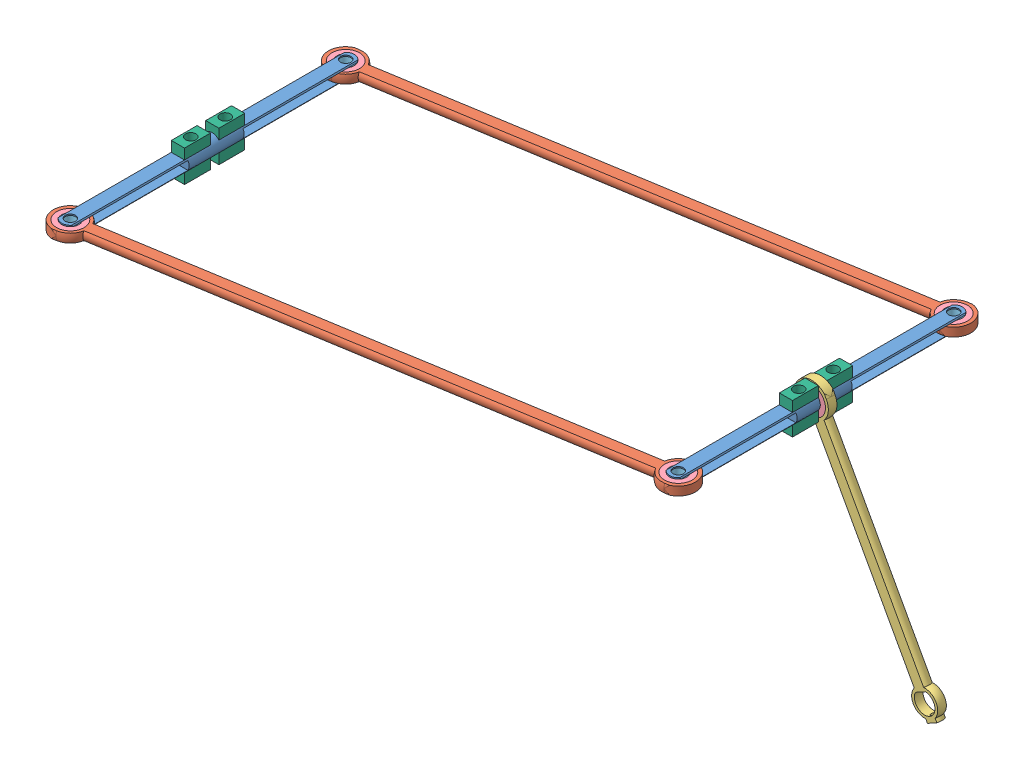
SolidWorks assembly 单臂, configuration 默认. Lengths in mm.
Overall size (196.95 72.97 116.28).
22 component instances, 6 part files, 52 mates.
Components (placement in the parent):
- 关节-1: 关节 [默认] at (38.3387 -1.1505 -161.6361) size (5 5 85)
- 关节-2: 关节 [默认] at (-113.5016 -1.1505 -136.8395) size (5 5 85)
- 长臂-1: 长臂 [默认] at (-126.4048 -1.1505 -124.7323) x (0.986926 0 -0.161172) z (0.161172 0 0.986926) size (163.85 2.5 10)
- 长臂-2: 长臂 [默认] at (-126.4048 -1.1505 -44.7323) x (0.986926 0 -0.161172) z (0.161172 0 0.986926) size (163.85 2.5 10)
- 短臂-1: 短臂 [默认] at (78.8008 -74.9015 -111.6361) x (-0.480997 0.876722 0) z (0.876722 0.480997 0) size (77.74 2.5 10)
- 轴承_MR85ZZ-1: 轴承_MR85ZZ [默认] at (38.3387 -1.1505 -112.8861) size (8 8 2.5)
- 轴承_MR85ZZ-2: 轴承_MR85ZZ [默认] at (38.3387 0.0995 -71.6361) x (1 0 0) z (0 -1 0) size (8 8 2.5)
- 轴承_MR85ZZ-3: 轴承_MR85ZZ [默认] at (-113.5016 0.0995 -46.8395) x (1 0 0) z (0 -1 0) size (8 8 2.5)
- 轴承_MR85ZZ-4: 轴承_MR85ZZ [默认] at (-113.5016 0.0995 -126.8395) x (1 0 0) z (0 -1 0) size (8 8 2.5)
- 轴承_MR85ZZ-5: 轴承_MR85ZZ [默认] at (38.3387 0.0995 -151.6361) x (1 0 0) z (0 -1 0) size (8 8 2.5)
- 长臂_关节连接件-1: 长臂_关节连接件 [默认] at (-113.5016 -2.4005 -126.8395) x (1 0 0) z (0 1 0) size (5 5 2.5)
- 长臂_关节连接件-2: 长臂_关节连接件 [默认] at (38.3387 0.0995 -151.6361) x (1 0 0) z (0 -1 0) size (5 5 2.5)
- 长臂_关节连接件-3: 长臂_关节连接件 [默认] at (38.3387 0.0995 -71.6361) x (1 0 0) z (0 -1 0) size (5 5 2.5)
- 长臂_关节连接件-4: 长臂_关节连接件 [默认] at (-113.5016 0.0995 -46.8395) x (1 0 0) z (0 -1 0) size (5 5 2.5)
- 短臂-关节轴承限位件-1: 短臂-关节轴承限位件 [默认] at (-115.3656 3.4495 -82.9304) x (0 0 1) z (0 -1 0) size (7.5 3.84 3)
- 短臂-关节轴承限位件-2: 短臂-关节轴承限位件 [默认] at (-115.3656 -2.7505 -92.9304) x (0 0 1) z (0 -1 0) size (7.5 3.84 3)
- 短臂-关节轴承限位件-3: 短臂-关节轴承限位件 [默认] at (-115.3656 3.4495 -92.9304) x (0 0 1) z (0 -1 0) size (7.5 3.84 3)
- 短臂-关节轴承限位件-4: 短臂-关节轴承限位件 [默认] at (-115.3656 -2.7505 -82.9304) x (0 0 1) z (0 -1 0) size (7.5 3.84 3)
- 短臂-关节轴承限位件-5: 短臂-关节轴承限位件 [默认] at (36.4746 -2.7505 -117.727) x (0 0 1) z (0 -1 0) size (7.5 3.84 3)
- 短臂-关节轴承限位件-6: 短臂-关节轴承限位件 [默认] at (36.4746 3.4495 -107.727) x (0 0 1) z (0 -1 0) size (7.5 3.84 3)
- 短臂-关节轴承限位件-7: 短臂-关节轴承限位件 [默认] at (36.4746 3.4495 -117.727) x (0 0 1) z (0 -1 0) size (7.5 3.84 3)
- 短臂-关节轴承限位件-8: 短臂-关节轴承限位件 [默认] at (36.4746 -2.7505 -107.727) x (0 0 1) z (0 -1 0) size (7.5 3.84 3)
Mates (geometry in assembly coordinates):
- 同心3: concentric aligned: cylinder of 关节-1 through (38.3387 -1.1505 -61.6361) axis (0 0 -1) radius 2.5; cylinder of 轴承_MR85ZZ-1 through (38.3387 -1.1505 -110.3861) axis (0 0 -1) radius 2.5
- 重合2: coincident aligned: plane of 关节-1 through (38.3387 -1.1505 -110.3861) normal (0 0 1); plane of 轴承_MR85ZZ-1 through (38.3387 -1.1505 -110.3861) normal (0 0 1)
- 同心4: concentric anti-aligned: cylinder of 关节-1 through (38.3387 20.8495 -71.6361) axis (0 -1 0) radius 1.5; cylinder of 轴承_MR85ZZ-2 through (38.3387 -2.4005 -71.6361) axis (0 1 0) radius 2.5
- 重合4: coincident anti-aligned: plane of 关节-1 through (60.3387 0.0995 -39.6361) normal (0 -1 0); plane of 轴承_MR85ZZ-2 through (38.3387 0.0995 -71.6361) normal (0 1 0)
- 重合7: coincident anti-aligned: plane of 关节-1 through (60.3387 0.0995 -183.6361) normal (0 -1 0); plane of 轴承_MR85ZZ-5 through (38.3387 0.0995 -151.6361) normal (0 1 0)
- 同心7: concentric anti-aligned: cylinder of 关节-1 through (38.3387 20.8495 -151.6361) axis (0 -1 0) radius 1.5; cylinder of 轴承_MR85ZZ-5 through (38.3387 -2.4005 -151.6361) axis (0 1 0) radius 2.5
- 同心10: concentric aligned: cylinder of 轴承_MR85ZZ-3 through (-113.5016 -2.4005 -46.8395) axis (0 1 0) radius 2.5; circle of 关节-2
- 重合10: coincident anti-aligned: plane of 轴承_MR85ZZ-3 through (-113.5016 0.0995 -46.8395) normal (0 1 0); plane of 关节-2 through (-91.5016 0.0995 -14.8395) normal (0 -1 0)
- 重合11: coincident anti-aligned: plane of 轴承_MR85ZZ-4 through (-113.5016 0.0995 -126.8395) normal (0 1 0); plane of 关节-2 through (-91.5016 0.0995 -158.8395) normal (0 -1 0)
- 同心11: concentric anti-aligned: cylinder of 关节-2 through (-113.5016 20.8495 -126.8395) axis (0 -1 0) radius 1.5; cylinder of 轴承_MR85ZZ-4 through (-113.5016 -2.4005 -126.8395) axis (0 1 0) radius 2.5
- 同心6: concentric anti-aligned: cylinder of 长臂-1 through (38.3387 168.8495 -151.6361) axis (0 -1 0) radius 4; cylinder of 轴承_MR85ZZ-5 through (38.3387 -2.4005 -151.6361) axis (0 1 0) radius 4
- 重合6: coincident aligned: plane of 长臂-1 through (51.2419 0.0995 -153.7433) normal (0 1 0); plane of 轴承_MR85ZZ-5 through (38.3387 0.0995 -151.6361) normal (0 1 0)
- 同心9: concentric anti-aligned: cylinder of 长臂-1 through (-113.5016 168.8495 -126.8395) axis (0 -1 0) radius 4; cylinder of 轴承_MR85ZZ-4 through (-113.5016 -2.4005 -126.8395) axis (0 1 0) radius 4
- 重合9: coincident aligned: plane of 长臂-1 through (51.2419 0.0995 -153.7433) normal (0 1 0); plane of 轴承_MR85ZZ-4 through (-113.5016 0.0995 -126.8395) normal (0 1 0)
- 重合5: coincident aligned: plane of 长臂-2 through (51.2419 0.0995 -73.7433) normal (0 1 0); plane of 轴承_MR85ZZ-2 through (38.3387 0.0995 -71.6361) normal (0 1 0)
- 同心5: concentric anti-aligned: cylinder of 长臂-2 through (38.3387 168.8495 -71.6361) axis (0 -1 0) radius 4; cylinder of 轴承_MR85ZZ-2 through (38.3387 -2.4005 -71.6361) axis (0 1 0) radius 4
- 同心8: concentric anti-aligned: cylinder of 长臂-2 through (-113.5016 168.8495 -46.8395) axis (0 -1 0) radius 4; cylinder of 轴承_MR85ZZ-3 through (-113.5016 -2.4005 -46.8395) axis (0 1 0) radius 4
- 重合8: coincident aligned: plane of 长臂-2 through (51.2419 0.0995 -73.7433) normal (0 1 0); plane of 轴承_MR85ZZ-3 through (-113.5016 0.0995 -46.8395) normal (0 1 0)
- 同心2: concentric anti-aligned: cylinder of 轴承_MR85ZZ-1 through (38.3387 -1.1505 -110.3861) axis (0 0 -1) radius 4; cylinder of 短臂-1 through (38.3387 -1.1505 -210.3861) axis (0 0 1) radius 4
- 重合1: coincident aligned: plane of 轴承_MR85ZZ-1 through (38.3387 -1.1505 -110.3861) normal (0 0 1); plane of 短臂-1 through (30.7011 12.7707 -110.3861) normal (0 0 1)
- 同心12: concentric anti-aligned: cylinder of 轴承_MR85ZZ-4 through (-113.5016 -2.4005 -126.8395) axis (0 1 0) radius 2.5; cylinder of 长臂_关节连接件-1 through (-113.5016 0.0995 -126.8395) axis (0 -1 0) radius 2.5
- 重合12: coincident aligned: plane of 轴承_MR85ZZ-4 through (-113.5016 0.0995 -126.8395) normal (0 1 0); plane of 长臂_关节连接件-1 through (-113.5016 0.0995 -126.8395) normal (0 1 0)
- 同心13: concentric anti-aligned: cylinder of 关节-2 through (-113.5016 20.8495 -46.8395) axis (0 -1 0) radius 1.5; cylinder of 长臂_关节连接件-4 through (-113.5016 -2.4005 -46.8395) axis (0 1 0) radius 1.5
- 重合13: coincident aligned: plane of 轴承_MR85ZZ-3 through (-113.5016 0.0995 -46.8395) normal (0 1 0); plane of 长臂_关节连接件-4 through (-113.5016 0.0995 -46.8395) normal (0 1 0)
- 同心14: concentric anti-aligned: cylinder of 关节-1 through (38.3387 20.8495 -151.6361) axis (0 -1 0) radius 1.5; cylinder of 长臂_关节连接件-2 through (38.3387 -2.4005 -151.6361) axis (0 1 0) radius 1.5
- 重合14: coincident aligned: plane of 轴承_MR85ZZ-5 through (38.3387 0.0995 -151.6361) normal (0 1 0); plane of 长臂_关节连接件-2 through (38.3387 0.0995 -151.6361) normal (0 1 0)
- 同心15: concentric anti-aligned: cylinder of 关节-1 through (38.3387 20.8495 -71.6361) axis (0 -1 0) radius 1.5; cylinder of 长臂_关节连接件-3 through (38.3387 -2.4005 -71.6361) axis (0 1 0) radius 1.5
- 重合15: coincident aligned: plane of 轴承_MR85ZZ-2 through (38.3387 0.0995 -71.6361) normal (0 1 0); plane of 长臂_关节连接件-3 through (38.3387 0.0995 -71.6361) normal (0 1 0)
- 同心16: concentric anti-aligned: cylinder of 关节-2 through (-113.5016 20.8495 -81.8395) axis (0 -1 0) radius 1.5; cylinder of 短臂-关节轴承限位件-1 through (-113.5016 0.4495 -81.8395) axis (0 1 0) radius 1.5
- 重合16: coincident anti-aligned: plane of 关节-2 through (-113.5016 -1.1505 -85.5895) normal (0 0 1); plane of 短臂-关节轴承限位件-1 through (-115.4216 0.4495 -85.5895) normal (0 0 -1)
- 重合19: coincident anti-aligned: plane of 关节-2 through (-113.5016 -1.1505 -88.0895) normal (0 0 -1); plane of 短臂-关节轴承限位件-3 through (-115.4216 0.4495 -88.0895) normal (0 0 1)
- 同心19: concentric anti-aligned: cylinder of 关节-2 through (-113.5016 20.8495 -91.8395) axis (0 -1 0) radius 1.5; cylinder of 短臂-关节轴承限位件-3 through (-113.5016 0.4495 -91.8395) axis (0 1 0) radius 1.5
- 重合20: coincident anti-aligned: plane of 关节-2 through (-113.5016 -1.1505 -88.0895) normal (0 0 -1); plane of 短臂-关节轴承限位件-2 through (-115.4216 -5.7505 -88.0895) normal (0 0 1)
- 同心21: concentric anti-aligned: cylinder of 关节-2 through (-113.5016 20.8495 -91.8395) axis (0 -1 0) radius 1.5; cylinder of 短臂-关节轴承限位件-2 through (-113.5016 -5.7505 -91.8395) axis (0 1 0) radius 1.5
- 重合21: coincident anti-aligned: plane of 关节-2 through (-113.5016 -2.7505 -36.8395) normal (0 -1 0); plane of 短臂-关节轴承限位件-2 through (-115.3656 -2.7505 -92.9304) normal (0 1 0)
- 重合22: coincident: plane of 关节-2 through (-113.5016 0.4495 -36.8395) normal (0 1 0); line of 短臂-关节轴承限位件-3 through (-115.4216 0.4495 -88.0895) axis (0 0 -1)
- 重合23: coincident anti-aligned: plane of 关节-2 through (-113.5016 0.4495 -136.8395) normal (0 1 0); plane of 短臂-关节轴承限位件-1 through (-115.3656 0.4495 -82.9304) normal (0 -1 0)
- 重合24: coincident anti-aligned: plane of 关节-2 through (-113.5016 -2.7505 -136.8395) normal (0 -1 0); plane of 短臂-关节轴承限位件-4 through (-115.3656 -2.7505 -82.9304) normal (0 1 0)
- 同心22: concentric anti-aligned: cylinder of 关节-2 through (-113.5016 20.8495 -81.8395) axis (0 -1 0) radius 1.5; cylinder of 短臂-关节轴承限位件-4 through (-113.5016 -5.7505 -81.8395) axis (0 1 0) radius 1.5
- 重合25: coincident anti-aligned: plane of 关节-2 through (-113.5016 -1.1505 -85.5895) normal (0 0 1); plane of 短臂-关节轴承限位件-4 through (-115.4216 -5.7505 -85.5895) normal (0 0 -1)
- 同心23: concentric anti-aligned: cylinder of 关节-1 through (38.3387 20.8495 -106.6361) axis (0 -1 0) radius 1.5; cylinder of 短臂-关节轴承限位件-6 through (38.3387 0.4495 -106.6361) axis (0 1 0) radius 1.5
- 重合26: coincident anti-aligned: plane of 关节-1 through (38.3387 0.4495 -161.6361) normal (0 1 0); plane of 短臂-关节轴承限位件-6 through (36.4746 0.4495 -107.727) normal (0 -1 0)
- 重合27: coincident anti-aligned: plane of 关节-1 through (38.3387 -2.7505 -161.6361) normal (0 -1 0); plane of 短臂-关节轴承限位件-8 through (36.4746 -2.7505 -107.727) normal (0 1 0)
- 同心24: concentric anti-aligned: cylinder of 关节-1 through (38.3387 20.8495 -106.6361) axis (0 -1 0) radius 1.5; cylinder of 短臂-关节轴承限位件-8 through (38.3387 -5.7505 -106.6361) axis (0 1 0) radius 1.5
- 重合28: coincident anti-aligned: plane of 短臂-1 through (30.7011 12.7707 -110.3861) normal (0 0 1); plane of 短臂-关节轴承限位件-8 through (36.4187 -5.7505 -110.3861) normal (0 0 -1)
- 重合29: coincident anti-aligned: plane of 轴承_MR85ZZ-1 through (38.3387 -1.1505 -110.3861) normal (0 0 1); plane of 短臂-关节轴承限位件-6 through (36.4187 0.4495 -110.3861) normal (0 0 -1)
- 同心25: concentric anti-aligned: cylinder of 关节-1 through (38.3387 20.8495 -116.6361) axis (0 -1 0) radius 1.5; cylinder of 短臂-关节轴承限位件-7 through (38.3387 0.4495 -116.6361) axis (0 1 0) radius 1.5
- 重合30: coincident anti-aligned: plane of 关节-1 through (38.3387 0.4495 -61.6361) normal (0 1 0); plane of 短臂-关节轴承限位件-7 through (36.4746 0.4495 -117.727) normal (0 -1 0)
- 重合31: coincident anti-aligned: plane of 短臂-1 through (30.7011 12.7707 -112.8861) normal (0 0 -1); plane of 短臂-关节轴承限位件-7 through (36.4187 0.4495 -112.8861) normal (0 0 1)
- 重合32: coincident anti-aligned: plane of 关节-1 through (38.3387 -2.7505 -61.6361) normal (0 -1 0); plane of 短臂-关节轴承限位件-5 through (36.4746 -2.7505 -117.727) normal (0 1 0)
- 同心26: concentric anti-aligned: cylinder of 关节-1 through (38.3387 20.8495 -116.6361) axis (0 -1 0) radius 1.5; cylinder of 短臂-关节轴承限位件-5 through (38.3387 -5.7505 -116.6361) axis (0 1 0) radius 1.5
- 重合33: coincident anti-aligned: plane of 轴承_MR85ZZ-1 through (38.3387 -1.1505 -112.8861) normal (0 0 -1); plane of 短臂-关节轴承限位件-5 through (36.4187 -5.7505 -112.8861) normal (0 0 1)
